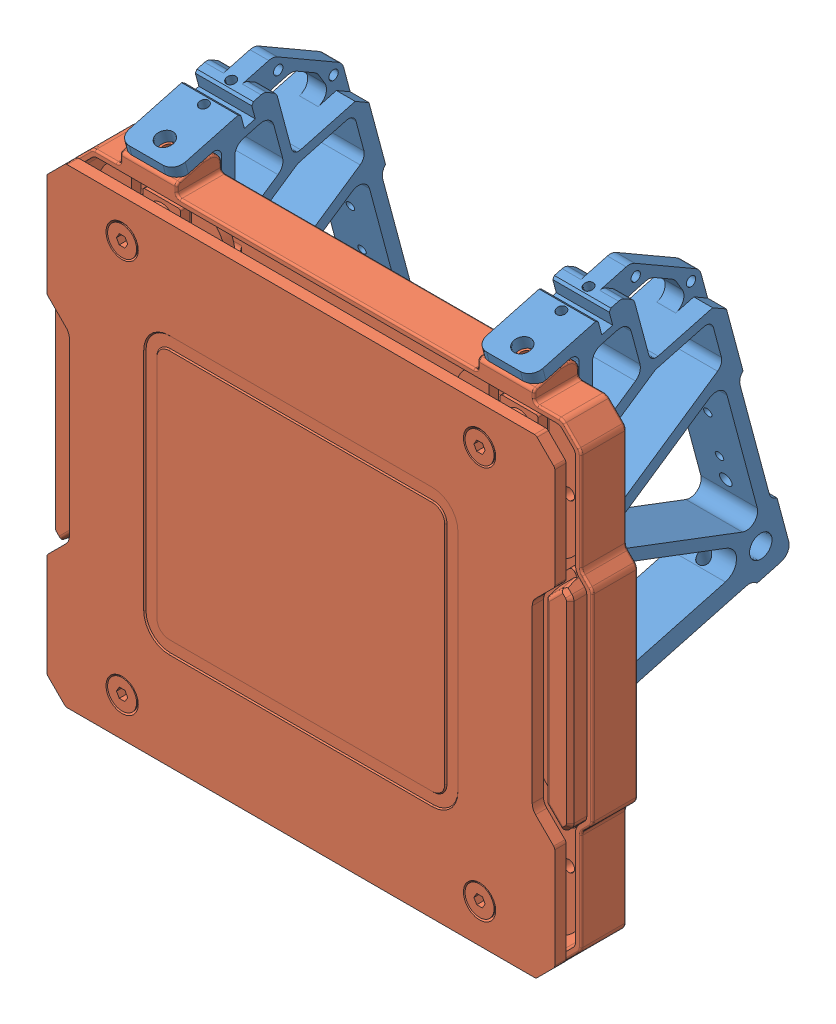
SolidWorks assembly 小装甲, configuration 默认. Lengths in mm.
Overall size (141 139.38 74.79).
3 component instances, 2 part files, 17 mates.
Components (placement in the parent):
- 二版RM2019裁判系统支撑架AH02-1: 二版RM2019裁判系统支撑架AH02 [默认] at (-45.6645 -48.283 152.6103) size (15 130.97 68.39)
- 二版RM2019裁判系统支撑架AH02-2: 二版RM2019裁判系统支撑架AH02 [默认] at (49.3355 -48.283 152.6103) size (15 130.97 68.39)
- 二版RM2019裁判系统装甲模块AM02-1: 二版RM2019裁判系统装甲模块AM02 [默认] at (-43.1689 -91.0852 179.4707) x (0 0 1) z (-1 0 0) size (19 129.97 141)
Mates (geometry in assembly coordinates):
- 重合1: coincident anti-aligned: plane of 二版RM2019裁判系统支撑架AH02-1 through (-3.4824 44.8918 152.6103) normal (0 0.965926 0.258819); plane of ? through (-53.1645 50.7171 130.8702) normal (0 -0.965926 -0.258819)
- 同心1: concentric aligned: cylinder of 二版RM2019裁判系统支撑架AH02-1 through (-45.6645 39.8055 148.2611) axis (0 0.965926 0.258819) radius 1.25; cylinder of ? through (-45.6645 38.8769 148.0122) axis (0 0.965926 0.258819) radius 1.5
- 同心2: concentric aligned: cylinder of 二版RM2019裁判系统支撑架AH02-1 through (-45.6645 40.7325 140.7449) axis (0 0.965926 0.258819) radius 1.25; cylinder of ? through (-45.6645 40.8181 140.7678) axis (0 0.965926 0.258819) radius 1.5
- 重合4: coincident anti-aligned: plane of 二版RM2019裁判系统支撑架AH02-2 through (91.5176 44.8918 152.6103) normal (0 0.965926 0.258819); plane of ? through (41.8355 50.7171 130.8702) normal (0 -0.965926 -0.258819)
- 同心5: concentric aligned: cylinder of 二版RM2019裁判系统支撑架AH02-2 through (49.3355 39.8055 148.2611) axis (0 0.965926 0.258819) radius 1.25; cylinder of ? through (49.3355 38.8769 148.0122) axis (0 0.965926 0.258819) radius 1.5
- 同心6: concentric aligned: cylinder of 二版RM2019裁判系统支撑架AH02-2 through (49.3355 40.7325 140.7449) axis (0 0.965926 0.258819) radius 1.25; cylinder of ? through (49.3355 40.8181 140.7678) axis (0 0.965926 0.258819) radius 1.5
- 同心7: concentric: cylinder of ? through (-45.6645 57.3423 148.0942) axis (0 0.258819 -0.965926) radius 2.25; cylinder of ? through (-45.6645 59.9305 138.435) axis (0 -0.258819 0.965926) radius 1.65
- 重合5: coincident: plane of ? through (-24.0453 53.1691 136.6232) normal (0 0.258819 -0.965926); plane of ? through (-38.1645 53.1541 136.6192) normal (0 -0.258819 0.965926)
- 平行1: parallel: plane of ? through (-53.1645 53.1 136.7428) normal (0 0.866025 0.5); plane of ? through (1.8355 87.5118 77.11) normal (0 -0.866025 -0.5)
- 同心8: concentric: cylinder of ? through (49.3355 59.9305 138.435) axis (0 -0.258819 0.965926) radius 1.65; cylinder of ? through (49.3355 57.3423 148.0942) axis (0 0.258819 -0.965926) radius 2.25
- 重合6: coincident: plane of ? through (-38.1645 53.1541 136.6192) normal (0 -0.258819 0.965926); plane of ? through (70.9547 53.1691 136.6232) normal (0 0.258819 -0.965926)
- 平行2: parallel: plane of ? through (1.8355 87.5118 77.11) normal (0 -0.866025 -0.5); plane of ? through (41.8355 53.1 136.7428) normal (0 0.866025 0.5)
- 重合8: coincident anti-aligned: plane of 二版RM2019裁判系统支撑架AH02-2 through (27.7162 41.5789 152.6103) normal (0 -0.965926 -0.258819); plane of ? through (41.8355 41.5809 152.6031) normal (0 0.965926 0.258819)
- 同心9: concentric anti-aligned: cylinder of 二版RM2019裁判系统支撑架AH02-2 through (49.3355 49.4244 161.9676) axis (0 -0.965926 -0.258819) radius 2.25; cylinder of ? through (49.3355 39.7651 159.3794) axis (0 0.965926 0.258819) radius 1.65
- 同心10: concentric anti-aligned: cylinder of 二版RM2019裁判系统支撑架AH02-1 through (-45.6645 49.4244 161.9676) axis (0 -0.965926 -0.258819) radius 2.25; cylinder of ? through (-45.6645 39.7651 159.3794) axis (0 0.965926 0.258819) radius 1.65
- 同心11: concentric aligned: cylinder of 二版RM2019裁判系统支撑架AH02-2 through (49.3355 49.4244 161.9676) axis (0 -0.965926 -0.258819) radius 2.25; circle of 二版RM2019裁判系统装甲模块AM02-1
- 同心12: concentric anti-aligned: cylinder of 二版RM2019裁判系统支撑架AH02-1 through (-45.6645 49.4244 161.9676) axis (0 -0.965926 -0.258819) radius 2.25; cylinder of 二版RM2019裁判系统装甲模块AM02-1 through (-45.6645 39.7651 159.3794) axis (0 0.965926 0.258819) radius 1.65
